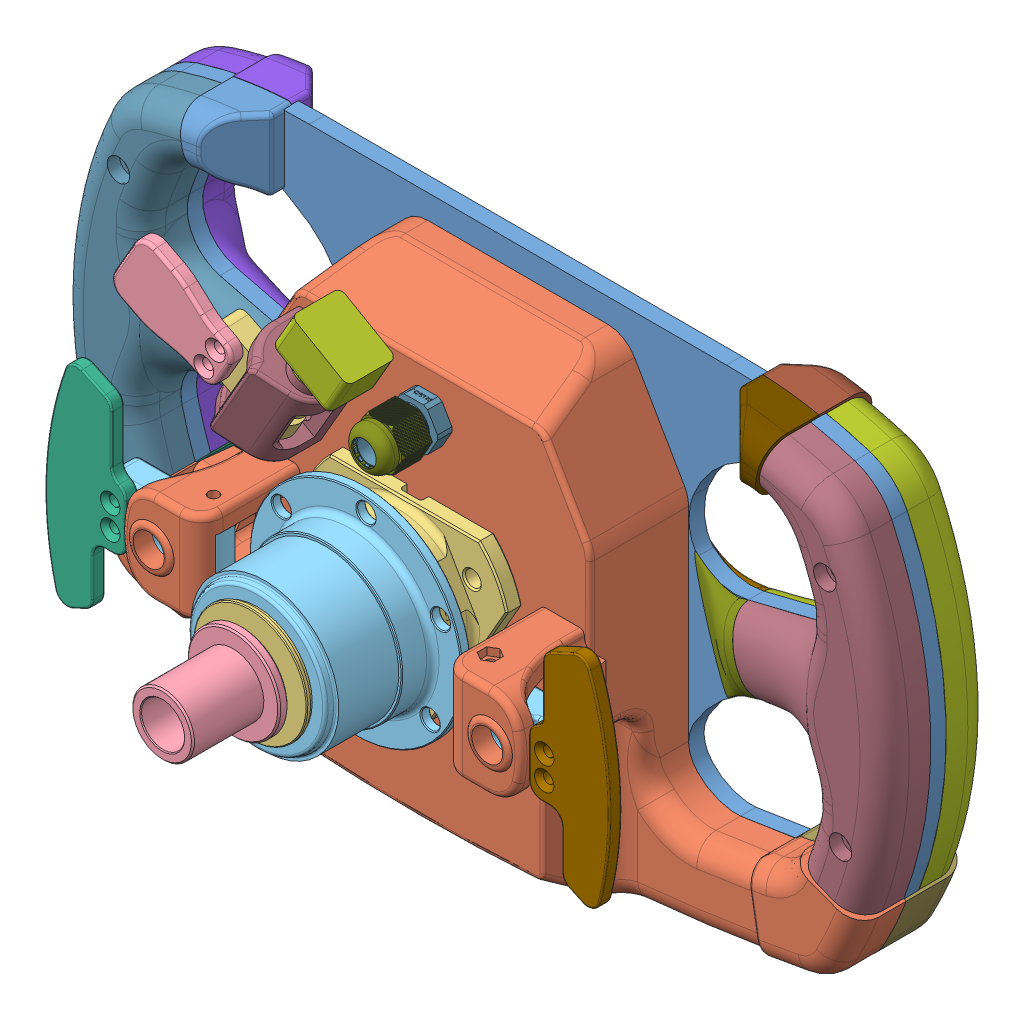
SolidWorks assembly zlozeniekiera, configuration Default. Lengths in mm.
Overall size (268.19 572.15 139.84).
49 component instances, 35 part files, 82 mates.
Components (placement in the parent):
- Złożenie1^zlozeniekiera-1: Złożenie1^zlozeniekiera [Domyślna] at (-0.1917 0.1107 0) size (268 154.26 5) (virtual)
  - rdzen-1: rdzen [Domyślna] at (-26.4708 14.9344 12.6876) size (268 154.26 5)
- tyl-1: tyl [Domyślna] at (-26.6625 15.0452 12.6876) size (252.17 146.43 32.01)
- F7_QUICK-RELEASE WITH CONNECTOR.stp-1: F7_QUICK-RELEASE WITH CONNECTOR.stp [Domyślna] at (-26.5641 11.2708 49.6876) x (0 0 1) z (0.5 0.866025 0) size (83.5 76.23 76.23)
  - TE501054mozzoQR210-3d.stp-1: TE501054mozzoQR210-3d.stp [Domyślna] at origin size (55 67.92 66.73)
  - TE501053pernoQR210-3d.stp-1: TE501053pernoQR210-3d.stp [Domyślna] at (83.5 0 0) x (-1 0 0) z (0 0 -1) size (65 30 30)
  - TE501060boccolaQR200-3d.stp-1: TE501060boccolaQR200-3d.stp [Domyślna] at (17.7 0 0) x (1 0 0) z (0 0.111007 0.99382) size (35 69 69)
- bloczek-1: bloczek [Default] at (-26.6646 -13.7657 17.6876) x (-0.5 -0.866025 0) z (0 0 1) size (69.35 63.49 30)
- raczka_gora-1: raczka_gora [Domyślna] at (-26.6625 15.0452 12.6876) size (62.1 126.32 17.56)
- el_dol_mirror-1: el_dol_mirror [Domyślna] at (-26.4925 15.0454 12.6876) size (268 572.04 21.84)
- el_maly_srodek-1: el_maly_srodek [Domyślna] at (-26.6625 15.0452 12.6876) size (51.95 50.83 19.34)
- el_maly_srodek_mirror-1: el_maly_srodek_mirror [Domyślna] at (-26.4708 14.9344 12.6876) size (51.95 50.83 19.34)
- el_maly_dol-1: el_maly_dol [Domyślna] at (-26.4708 14.9344 12.6876) size (268 572.04 21.84)
- el_maly_gora-1: el_maly_gora [Domyślna] at (-26.7685 15.0477 12.6876) size (51.35 102.79 24.34)
- raczka_dolna-1: raczka_dolna [Domyślna] at (-26.6625 15.0452 17.6876) size (62.1 126.32 19.37)
- raczka_dolna_mirror-1: raczka_dolna_mirror [Domyślna] at (-26.6625 15.0452 17.6876) size (62.1 126.32 19.37)
- el_gora_mirror-1: el_gora_mirror [Domyślna] at (-26.569 15.0807 12.6876) size (51.35 102.79 24.34)
- el_maly_srodek_tyl-1: el_maly_srodek_tyl [Domyślna] at (-26.6625 15.0452 17.6876) size (51.95 50.83 19.34)
- el_maly_srodek_tyl_mirror-1: el_maly_srodek_tyl_mirror [Domyślna] at (-26.6625 15.0452 17.6876) size (51.95 50.83 19.34)
- el_maly_tyl_dolny-1: el_maly_tyl_dolny [Domyślna] at (-26.4708 14.9344 17.6876) size (268 572.04 21.84)
- el_maly_tyl_dolny_mirror-1: el_maly_tyl_dolny_mirror [Domyślna] at (-26.4708 14.9344 17.6876) size (268 572.04 21.84)
- shifter_main_part_short_v2-1: shifter_main_part_short_v2 [Domyślna] at (141.4879 -1.0656 -23.9382) x (1 0 0) z (0 -1 0) size (35.26 33.03 30)
- shifter_main_part_short_v2-2: shifter_main_part_short_v2 [Domyślna] at (-194.4295 16.9344 -23.9382) x (-1 0 0) z (0 1 0) size (35.26 33.03 30)
- hinge_clutch_v3-1: hinge_clutch_v3 [Domyślna] at (-55.1652 55.5826 54.6884) x (0.865327 -0.499905 -0.036129) z (-0.500231 -0.865892 0) size (29 10 15.4)
- paddle_clutch-1: paddle_clutch [Domyślna] at (-89.6273 22.7425 71.1838) x (-0.865327 0.499905 0.036129) z (0.500231 0.865892 0) size (36 9 75.95)
- hinge_plaski_short-1: hinge_plaski_short [Domyślna] at (-71.3708 16.9544 66.7209) x (1 0 0) z (0 -1 0) size (36 10 17.76)
- paddle_left-1: paddle_left [Domyślna] at (-91.8708 -30.0206 81.7209) x (-1 0 0) z (0 1 0) size (33.6 9 75.95)
- hinge_plaski_short-2: hinge_plaski_short [Domyślna] at (18.4292 -1.0456 66.7209) x (-1 0 0) z (0 1 0) size (36 10 17.76)
- encoder_part-2: encoder_part [Domyślna] at (-61.5118 44.2357 59.6851) x (0 0 -1) z (0.500231 0.865892 0) size (15.93 21.21 25)
- raczka_gorna_mirror-1: raczka_gorna_mirror [Domyślna] at (-26.6625 15.0452 12.6876) size (62.1 126.32 17.56)
- paddle_right-1: paddle_right [Domyślna] at (38.9292 -30.0206 81.7209) x (-1 0 0) z (0 1 0) size (26.15 4 69.39)
- Rotary switch-1: Rotary switch [Default] at (-54.7755 49.4965 -0.5124) x (0.995388 0.095931 0) z (0 0 1) size (31 25 36.6)
- Rotary switch-2: Rotary switch [Default] at (-26.7755 58.4965 -0.5124) x (0.998607 -0.052769 0) z (0 0 1) size (31 25 36.6)
- Rotary switch-3: Rotary switch [Default] at (1.2245 49.4965 -0.5124) x (0.968702 0.248227 0) z (0 0 1) size (31 25 36.6)
- switch push button momentary-1: switch push button momentary [Default] at (-86.6625 -49.9694 13.3876) x (0.966368 -0.257164 0) z (0.257164 0.966368 0) size (17.68 19.1 17.68)
- switch push button momentary-2: switch push button momentary [Default] at (-106.5057 -47.4695 13.3876) x (0.954428 -0.298441 0) z (0.298441 0.954428 0) size (17.68 19.1 17.68)
- switch push button momentary-3: switch push button momentary [Default] at (33.3375 -49.9694 13.3876) x (0.653007 -0.757352 0) z (0.757352 0.653007 0) size (17.68 19.1 17.68)
- switch push button momentary-4: switch push button momentary [Default] at (53.1807 -47.4695 13.3876) x (-0.886715 -0.462316 0) z (0.462316 -0.886715 0) size (17.68 19.1 17.68)
- pokretlo-1: pokretlo [Domyślna] at (-54.7755 49.4965 5.4876) x (-0.935627 -0.352991 0) z (0 0 -1) size (14 13.72 7)
- pokretlo-2: pokretlo [Domyślna] at (-26.7755 58.4965 5.4876) x (0.994685 0.102965 0) z (0 0 -1) size (14 13.72 7)
- pokretlo-3: pokretlo [Domyślna] at (1.2245 49.4965 5.4876) x (-0.998139 -0.060976 0) z (0 0 -1) size (14 13.72 7)
- switch push button momentary-5: switch push button momentary [Default] at (-70.6625 -4.9548 13.3876) x (0.020325 0.999793 0) z (-0.999793 0.020325 0) size (17.68 19.1 17.68)
- switch push button momentary-6: switch push button momentary [Default] at (17.3375 -4.9548 13.3876) x (0.689884 -0.72392 0) z (0.72392 0.689884 0) size (17.68 19.1 17.68)
- clutch_v2_mirror-1: clutch_v2_mirror [Domyślna] at (130.9059 -51.9118 -23.7288) x (-0.865892 0.500231 0) z (0.500231 0.865892 0) size (34.6 31.24 30.75)
- mount_encoders-1: mount_encoders [Default] at (-26.7755 58.4965 12.6876) x (1 0 0) z (0 0 -1) size (71.49 25 2) (hidden)
- M12x1.5 Cable gland-1: M12x1.5 Cable gland [Default] at (-23.6718 57.843 54.9376) x (-0.99997 -0.00778 0) z (-0.00778 0.99997 0) size (16.05 30.89 14)
  - Cable gland-1: Cable gland [Default] at origin size (15.3 29.83 14)
  - Rubber gasket-1: Rubber gasket [Default] at (0 -6.81 0) x (-1 0 0) z (0 0 1) size (13.5 1.3 13.5)
  - M12 Domed nut-1: M12 Domed nut [Default] at (0 6.2 0) size (16.05 14.26 14)
Mates (geometry in assembly coordinates):
- Wspólnie3: coincident anti-aligned: plane of tyl-1 through (-26.6625 15.0452 49.6876) normal (0 0 1); plane of F7_QUICK-RELEASE WITH CONNECTOR.stp-1/TE501054mozzoQR210-3d.stp-1 through (-11.6252 2.6458 49.6876) normal (0 0 -1)
- Stycznie2: tangent: curve of raczka_gora-1; curve of pindol_srodek-1
- Wspólnie32: coincident aligned: line of raczka_dolna-1 through (55.332 2.0824 17.6876) axis (-0.286443 0.958097 0); line of pindol_srodek_dolny-1 through (55.332 2.0824 17.6876) axis (-0.286443 0.958097 0)
- Stycznie3: tangent: curve of raczka_dolna-1; curve of pindol_srodek_dolny-1
- Wspólnie35: coincident aligned: line of raczka_dolna_mirror-1 through (-108.657 2.0824 17.6876) axis (0.286443 0.958097 0); line of pindol_srodek_dolny_mirror-1 through (-108.657 2.0824 17.6876) axis (0.286443 0.958097 0)
- Stycznie4: tangent: curve of raczka_dolna_mirror-1; curve of pindol_srodek_dolny_mirror-1
- Koncentryczne10: concentric aligned: circle of hinge_clutch_v3-1; circle of paddle_clutch-1
- Koncentryczne11: concentric aligned: circle of hinge_clutch_v3-1; circle of paddle_clutch-1
- Wspólnie51: coincident anti-aligned: plane of hinge_clutch_v3-1 through (-62.5559 42.0672 64.6819) normal (0.031284 -0.018073 0.999347); plane of paddle_clutch-1 through (-89.815 22.8509 65.1877) normal (-0.031284 0.018073 -0.999347)
- Koncentryczne14: concentric anti-aligned: circle of hinge_plaski_short-1; circle of paddle_left-1
- Koncentryczne15: concentric anti-aligned: circle of hinge_plaski_short-1; circle of paddle_left-1
- Wspólnie52: coincident anti-aligned: plane of hinge_plaski_short-1 through (-71.3708 16.9544 75.7209) normal (0 0 1); plane of paddle_left-1 through (-91.8708 -30.0206 75.7209) normal (0 0 -1)
- Równolegle11: parallel anti-aligned: plane of tyl-1 through (-26.6625 15.0452 49.6876) normal (0 0 1); plane of encoder_part-2 through (-50.296 81.6416 51.7451) normal (0 0 -1)
- Wspólnie64: coincident anti-aligned: plane of el_gora_mirror-1 through (-143.6091 -40.3492 12.6876) normal (0.934673 0.35551 0); plane of raczka_gorna_mirror-1 through (-143.6802 -40.1623 7.6876) normal (-0.934673 -0.35551 0)
- Wspólnie66: coincident anti-aligned: plane of el_gora_mirror-1 through (-26.569 15.0807 -3.3124) normal (-0.35551 0.934673 0); plane of raczka_gorna_mirror-1 through (-26.6625 15.0452 -2.3124) normal (0.35551 -0.934673 0)
- Koncentryczne25: concentric aligned: circle of hinge_plaski_short-2; circle of paddle_right-1
- Koncentryczne26: concentric aligned: circle of hinge_plaski_short-2; circle of paddle_right-1
- Wspólnie67: coincident anti-aligned: plane of hinge_plaski_short-2 through (18.4292 -1.0456 75.7209) normal (0 0 1); plane of paddle_right-1 through (38.9292 -30.0206 75.7209) normal (0 0 -1)
- Równolegle12: parallel anti-aligned: plane of raczka_gora-1 through (-30.2176 5.6985 12.6876) normal (-0.35551 -0.934673 0); plane of el_maly_gora-1 through (-30.3947 5.514 12.6876) normal (0.35551 0.934673 0)
- Wspólnie68: coincident anti-aligned: plane of raczka_gora-1 through (90.3552 -40.1623 7.6876) normal (0.934673 -0.35551 0); plane of el_maly_gora-1 through (90.2715 -40.3823 12.6876) normal (-0.934673 0.35551 0)
- Koncentryczne303: concentric anti-aligned: circle of Rotary switch-1; circle of pokretlo-1
- Koncentryczne304: concentric aligned: circle of Rotary switch-2; circle of pokretlo-2
- Wspólnie76: coincident anti-aligned: plane of Rotary switch-2 through (-26.7755 58.4965 -0.5124) normal (0 0 -1); plane of pokretlo-2 through (-26.7755 58.4965 -0.5124) normal (0 0 1)
- Wspólnie77: coincident anti-aligned: plane of Rotary switch-1 through (-54.7755 49.4965 -0.5124) normal (0 0 -1); plane of pokretlo-1 through (-54.7755 49.4965 -0.5124) normal (0 0 1)
- Koncentryczne305: concentric anti-aligned: circle of Rotary switch-3; circle of pokretlo-3
- Wspólnie78: coincident anti-aligned: plane of Rotary switch-3 through (1.2245 49.4965 -0.5124) normal (0 0 -1); plane of pokretlo-3 through (1.2245 49.4965 -0.5124) normal (0 0 1)
- Koncentryczne308: concentric anti-aligned: circle of shifter_main_part_short_v2-2; circle of hinge_plaski_short-2
- Odległość10: distance = 0.1 mm anti-aligned: plane of hinge_plaski_short-2 through (36.2971 16.8344 75.7209) normal (0 1 0); plane of shifter_main_part_short_v2-2 through (-194.4295 16.9344 -23.9382) normal (0 -1 0)
- Koncentryczne314: concentric aligned: circle of shifter_main_part_short_v2-1; circle of hinge_plaski_short-1
- Odległość12: distance = 0.1 mm anti-aligned: plane of hinge_plaski_short-1 through (-89.2388 16.8344 75.7209) normal (0 1 0); plane of shifter_main_part_short_v2-1 through (141.4879 16.9344 -23.9382) normal (0 -1 0)
- Wspólnie84: coincident anti-aligned: plane of tyl-1 through (-26.6625 15.0452 49.6876) normal (0 0 1); plane of shifter_main_part_short_v2-2 through (-194.4295 16.9344 49.6876) normal (0 0 -1)
- Wspólnie85: coincident anti-aligned: plane of tyl-1 through (-26.6625 15.0452 49.6876) normal (0 0 1); plane of shifter_main_part_short_v2-1 through (141.4879 -1.0656 49.6876) normal (0 0 -1)
- Równolegle13: parallel aligned: plane of tyl-1 through (-81.3426 46.6342 32.6876) normal (-0.865892 0.500231 0); plane of clutch_v2_mirror-1 through (-68.5598 63.3208 -23.7288) normal (-0.865892 0.500231 0)
- Wspólnie86: coincident anti-aligned: plane of tyl-1 through (-26.6625 15.0452 49.6876) normal (0 0 1); plane of clutch_v2_mirror-1 through (130.9059 -51.9118 49.6876) normal (0 0 -1)
- Koncentryczne319: concentric aligned: circle of encoder_part-2; circle of clutch_v2_mirror-1
- Wspólnie87: coincident anti-aligned: plane of encoder_part-2 through (-50.5067 63.2853 59.6851) normal (-0.500231 -0.865892 0); plane of clutch_v2_mirror-1 through (135.408 -44.1188 -23.7288) normal (0.500231 0.865892 0)
- Wspólnie88: coincident anti-aligned: plane of Złożenie1^zlozeniekiera-1/rdzen-1 through (-26.6625 15.0452 17.6876) normal (0 0 1); plane of tyl-1 through (-26.6625 15.0452 17.6876) normal (0 0 -1)
- Wspólnie89: coincident anti-aligned: plane of Złożenie1^zlozeniekiera-1/rdzen-1 through (-26.6625 15.0452 17.6876) normal (0 0 1); plane of bloczek-1 through (-26.6646 -13.7657 17.6876) normal (0 0 -1)
- Zablokuj3: lock: unknown of Złożenie1^zlozeniekiera-1/rdzen-1; unknown of raczka_gora-1
- Wspólnie90: coincident anti-aligned: plane of Złożenie1^zlozeniekiera-1/rdzen-1 through (-26.6625 15.0452 12.6876) normal (0 0 -1); plane of el_dol_mirror-1 through (-26.4925 15.0454 12.6876) normal (0 0 1)
- Wspólnie91: coincident anti-aligned: plane of Złożenie1^zlozeniekiera-1/rdzen-1 through (-26.6625 15.0452 12.6876) normal (0 0 -1); plane of el_maly_srodek-1 through (42.1726 35.6249 12.6876) normal (0 0 1)
- Wspólnie92: coincident anti-aligned: plane of Złożenie1^zlozeniekiera-1/rdzen-1 through (-26.6625 15.0452 12.6876) normal (0 0 -1); plane of el_maly_srodek_mirror-1 through (-95.3059 35.5141 12.6876) normal (0 0 1)
- Wspólnie93: coincident anti-aligned: plane of Złożenie1^zlozeniekiera-1/rdzen-1 through (-26.6625 15.0452 12.6876) normal (0 0 -1); plane of el_maly_dol-1 through (-26.4708 14.9344 12.6876) normal (0 0 1)
- Wspólnie94: coincident anti-aligned: plane of Złożenie1^zlozeniekiera-1/rdzen-1 through (-26.6625 15.0452 12.6876) normal (0 0 -1); plane of el_maly_gora-1 through (-26.7685 15.0477 12.6876) normal (0 0 1)
- Wspólnie95: coincident anti-aligned: plane of Złożenie1^zlozeniekiera-1/rdzen-1 through (-26.6625 15.0452 17.6876) normal (0 0 1); plane of raczka_dolna-1 through (48.1635 26.0597 17.6876) normal (0 0 -1)
- Wspólnie96: coincident aligned: circle of Złożenie1^zlozeniekiera-1/rdzen-1; circle of raczka_dolna-1
- Wspólnie97: coincident anti-aligned: plane of Złożenie1^zlozeniekiera-1/rdzen-1 through (-26.6625 15.0452 17.6876) normal (0 0 1); plane of raczka_dolna_mirror-1 through (-101.4885 26.0597 17.6876) normal (0 0 -1)
- Wspólnie98: coincident anti-aligned: circle of Złożenie1^zlozeniekiera-1/rdzen-1; circle of raczka_dolna_mirror-1
- Wspólnie99: coincident anti-aligned: plane of Złożenie1^zlozeniekiera-1/rdzen-1 through (-26.6625 15.0452 12.6876) normal (0 0 -1); plane of el_gora_mirror-1 through (-26.569 15.0807 12.6876) normal (0 0 1)
- Wspólnie100: coincident anti-aligned: plane of Złożenie1^zlozeniekiera-1/rdzen-1 through (-26.6625 15.0452 17.6876) normal (0 0 1); plane of el_maly_srodek_tyl-1 through (42.1726 35.6249 17.6876) normal (0 0 -1)
- Wspólnie101: coincident anti-aligned: circle of Złożenie1^zlozeniekiera-1/rdzen-1; circle of raczka_dolna-1
- Wspólnie102: coincident anti-aligned: plane of Złożenie1^zlozeniekiera-1/rdzen-1 through (-26.6625 15.0452 17.6876) normal (0 0 1); plane of el_maly_srodek_tyl_mirror-1 through (-95.4976 35.6249 17.6876) normal (0 0 -1)
- Wspólnie103: coincident aligned: circle of Złożenie1^zlozeniekiera-1/rdzen-1; circle of raczka_dolna_mirror-1
- Wspólnie104: coincident anti-aligned: plane of Złożenie1^zlozeniekiera-1/rdzen-1 through (-26.6625 15.0452 17.6876) normal (0 0 1); plane of el_maly_tyl_dolny-1 through (-26.4708 14.9344 17.6876) normal (0 0 -1)
- Wspólnie107: coincident anti-aligned: plane of Złożenie1^zlozeniekiera-1/rdzen-1 through (-26.6625 15.0452 17.6876) normal (0 0 1); plane of el_maly_tyl_dolny_mirror-1 through (-26.4708 14.9344 17.6876) normal (0 0 -1)
- Koncentryczne320: concentric anti-aligned: circle of Złożenie1^zlozeniekiera-1/rdzen-1; circle of raczka_gorna_mirror-1
- Wspólnie109: coincident anti-aligned: plane of Złożenie1^zlozeniekiera-1/rdzen-1 through (-26.6625 15.0452 12.6876) normal (0 0 -1); plane of raczka_gorna_mirror-1 through (-101.4885 26.0597 12.6876) normal (0 0 1)
- Wspólnie110: coincident anti-aligned: circle of Złożenie1^zlozeniekiera-1/rdzen-1; circle of raczka_gorna_mirror-1
- Koncentryczne321: concentric aligned: circle of Złożenie1^zlozeniekiera-1/rdzen-1; circle of Rotary switch-1
- Wspólnie111: coincident aligned: plane of Złożenie1^zlozeniekiera-1/rdzen-1 through (-26.6625 15.0452 17.6876) normal (0 0 1); circle of Rotary switch-1
- Koncentryczne322: concentric aligned: cylinder of Złożenie1^zlozeniekiera-1/rdzen-1 through (-26.7755 58.4965 28.6876) axis (0 0 -1) radius 5; cylinder of Rotary switch-2 through (-26.7755 58.4965 10.2876) axis (0 0 -1) radius 2.35
- Wspólnie112: coincident anti-aligned: plane of Złożenie1^zlozeniekiera-1/rdzen-1 through (-26.6625 15.0452 17.6876) normal (0 0 1); plane of Rotary switch-2 through (-26.7755 58.4965 17.6876) normal (0 0 -1)
- Koncentryczne323: concentric aligned: cylinder of Złożenie1^zlozeniekiera-1/rdzen-1 through (1.2245 49.4965 28.6876) axis (0 0 -1) radius 5; cylinder of Rotary switch-3 through (1.2245 49.4965 10.2876) axis (0 0 -1) radius 2.35
- Wspólnie113: coincident anti-aligned: plane of Złożenie1^zlozeniekiera-1/rdzen-1 through (-26.6625 15.0452 17.6876) normal (0 0 1); plane of Rotary switch-3 through (1.2245 49.4965 17.6876) normal (0 0 -1)
- Koncentryczne324: concentric anti-aligned: circle of Złożenie1^zlozeniekiera-1/rdzen-1; circle of switch push button momentary-1
- Wspólnie114: coincident anti-aligned: plane of Złożenie1^zlozeniekiera-1/rdzen-1 through (-26.6625 15.0452 12.6876) normal (0 0 -1); plane of switch push button momentary-1 through (-86.6625 -49.9694 12.6876) normal (0 0 1)
- Koncentryczne325: concentric aligned: circle of Złożenie1^zlozeniekiera-1/rdzen-1; circle of switch push button momentary-2
- Wspólnie115: coincident anti-aligned: plane of Złożenie1^zlozeniekiera-1/rdzen-1 through (-26.6625 15.0452 12.6876) normal (0 0 -1); plane of switch push button momentary-2 through (-106.5057 -47.4695 12.6876) normal (0 0 1)
- Koncentryczne326: concentric aligned: circle of Złożenie1^zlozeniekiera-1/rdzen-1; circle of switch push button momentary-3
- Wspólnie116: coincident anti-aligned: plane of Złożenie1^zlozeniekiera-1/rdzen-1 through (-26.6625 15.0452 12.6876) normal (0 0 -1); plane of switch push button momentary-3 through (33.3375 -49.9694 12.6876) normal (0 0 1)
- Koncentryczne327: concentric aligned: circle of Złożenie1^zlozeniekiera-1/rdzen-1; circle of switch push button momentary-4
- Wspólnie117: coincident anti-aligned: plane of Złożenie1^zlozeniekiera-1/rdzen-1 through (-26.6625 15.0452 12.6876) normal (0 0 -1); plane of switch push button momentary-4 through (53.1807 -47.4695 12.6876) normal (0 0 1)
- Koncentryczne328: concentric aligned: circle of Złożenie1^zlozeniekiera-1/rdzen-1; circle of switch push button momentary-5
- Wspólnie118: coincident anti-aligned: plane of Złożenie1^zlozeniekiera-1/rdzen-1 through (-26.6625 15.0452 12.6876) normal (0 0 -1); plane of switch push button momentary-5 through (-70.6625 -4.9548 12.6876) normal (0 0 1)
- Koncentryczne329: concentric aligned: circle of Złożenie1^zlozeniekiera-1/rdzen-1; circle of switch push button momentary-6
- Wspólnie119: coincident anti-aligned: plane of Złożenie1^zlozeniekiera-1/rdzen-1 through (-26.6625 15.0452 12.6876) normal (0 0 -1); plane of switch push button momentary-6 through (17.3375 -4.9548 12.6876) normal (0 0 1)
- Zablokuj4: lock: unknown of Złożenie1^zlozeniekiera-1/rdzen-1; unknown of tyl-1
- Koncentryczne330: concentric aligned: circle of Złożenie1^zlozeniekiera-1/rdzen-1; circle of mount_encoders-1
- Koncentryczne331: concentric anti-aligned: circle of Złożenie1^zlozeniekiera-1/rdzen-1; circle of mount_encoders-1
- Wspólnie121: coincident anti-aligned: plane of Złożenie1^zlozeniekiera-1/rdzen-1 through (-26.6625 15.0452 12.6876) normal (0 0 -1); plane of mount_encoders-1 through (-26.7755 58.4965 12.6876) normal (0 0 1)
- Równolegle14: parallel anti-aligned: plane of tyl-1 through (-26.6625 15.0452 49.6876) normal (0 0 1); plane of M12x1.5 Cable gland-1/Cable gland-1 through (-23.6718 57.843 40.2876) normal (0 0 -1)
- Wspólnie122: coincident anti-aligned: plane of tyl-1 through (-26.6625 15.0452 49.6876) normal (0 0 1); plane of M12x1.5 Cable gland-1/Cable gland-1 through (-23.6718 57.843 49.6876) normal (0 0 -1)
